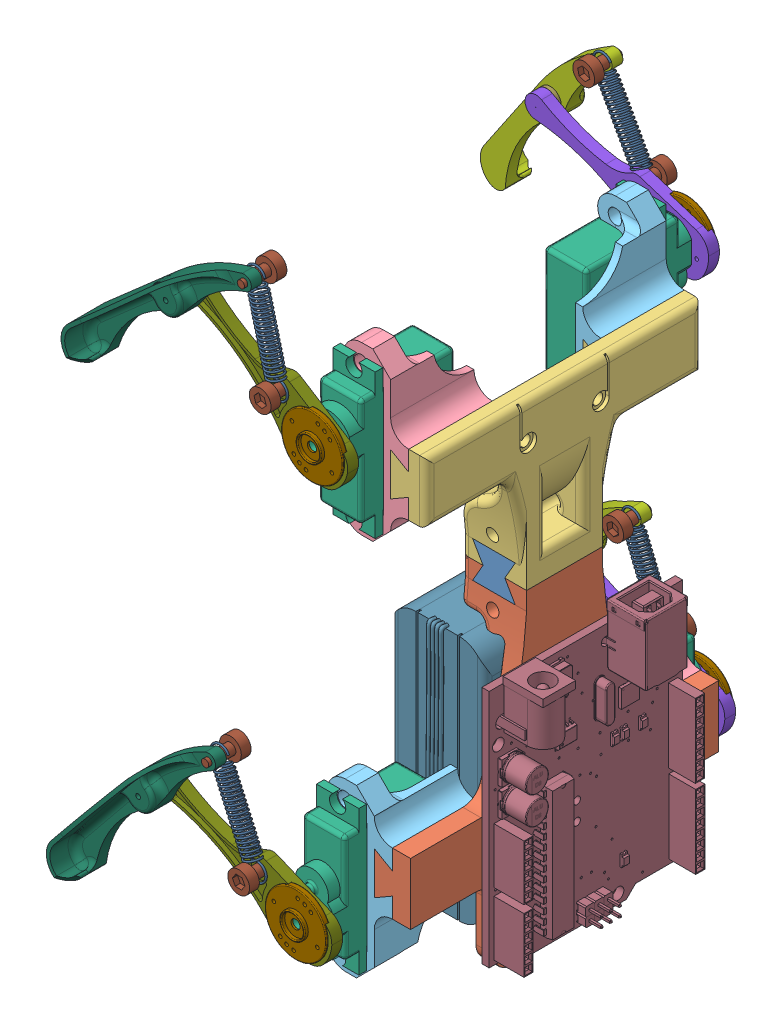
SolidWorks assembly puppy_v04_rigidSpine, configuration Default. Lengths in mm.
Overall size (92.78 186.66 133.4).
45 component instances, 16 part files, 43 mates.
Components (placement in the parent):
- rigid_spine-1: rigid_spine [Default] at (-4.6735 -0.0647 2.5101) size (11.77 10 21)
- body_front-1: body_front [Default] at (-4.6735 -65.0647 2.5101) x (0 0 1) z (1 0 0) size (85 87.52 18)
- body_rear-1: body_rear [Default] at (-4.6735 44.9353 2.5101) x (0 0 -1) z (1 0 0) size (76 45 18.96)
- HS-81MG_holder_empty-1: HS-81MG_holder_empty [Default] at (-13.6735 -61.0647 -34.9899) x (0 1 0) z (-1 0 0) size (46 23 17.9)
- HS-81MG_holder_empty-2: HS-81MG_holder_empty [Default] at (-13.6735 40.9353 35.5101) x (0 -1 0) z (-1 0 0) size (46 23 17.9)
- HS-81MG_holder_empty_mirror-1: HS-81MG_holder_empty_mirror [Default] at (-13.6735 -61.0647 40.0101) x (0 -1 0) z (-1 0 0) size (46 23 17.9)
- HS-81MG_holder_empty_mirror-2: HS-81MG_holder_empty_mirror [Default] at (-13.6735 40.9353 -30.4899) x (0 1 0) z (-1 0 0) size (46 23 17.9)
- HS-81MG-1: HS-81MG [Default] at (-13.6735 -61.0647 -33.0399) x (0 -1 0) z (1 0 0) size (39.8 33.1 11.7)
- HS-81MG-2: HS-81MG [Default] at (-13.6735 40.9353 -28.5399) x (0 1 0) z (-1 0 0) size (39.8 33.1 11.7)
- HS-81MG-3: HS-81MG [Default] at (-13.6735 -61.0647 38.0601) x (0 -1 0) z (-1 0 0) size (39.8 33.1 11.7)
- HS-81MG-4: HS-81MG [Default] at (-13.6735 40.9353 33.5601) x (0 1 0) z (1 0 0) size (39.8 33.1 11.7)
- AssemblyLeg_v2_left-1: AssemblyLeg_v2_left [Default] at (-36.9103 64.7215 -51.9489) x (0.561339 0.827586 0) z (-0.827586 0.561339 0) size (58.7 15.8 54.03)
  - LowerLeg_v2_left-1: LowerLeg_v2_left [Standard] at (-46.982 -8.259 12.3103) size (57 10 9.24)
  - UpperLeg_v2_left-1: UpperLeg_v2_left [Standard] at (-2.5862 -3.259 -29.832) x (-0.284896 0 0.958558) z (0 -1 0) size (52.5 13 3)
  - HS-81MG_horn-1: HS-81MG_horn [Default] at (-2.5862 -2.759 -29.832) x (-0.284896 0 0.958558) z (0 -1 0) size (17 17 5)
  - spring-2: spring [Default] at (-2.1428 -2.8777 -14.7648) x (0 1 0) z (0.451588 0 0.892227) size (5 5.5 30.5)
  - Schraube-2: Schraube [Standard] at (-3.2717 -0.159 -16.9953) x (0 -1 0) z (-0.448796 0 0.893634) size (9.7 6 6)
  - Schraube-3: Schraube [Standard] at (8.018 -5.359 5.3103) x (0 1 0) z (0.208882 0 0.977941) size (9.7 6 6)
  - spacerM3_1mm-1: spacerM3_1mm [Default] at (-13.982 -3.259 8.5103) x (1 0 0) z (0 1 0) size (6 6 1)
- AssemblyLeg_v2_left-2: AssemblyLeg_v2_left [Default] at (-34.5463 -44.4947 -56.4489) x (0.654125 0.756387 0) z (-0.756387 0.654125 0) size (58.7 15.8 54.03)
  - LowerLeg_v2_left-1: LowerLeg_v2_left [Standard] at (-46.982 -8.259 12.3103) size (57 10 9.24)
  - UpperLeg_v2_left-1: UpperLeg_v2_left [Standard] at (-2.5862 -3.259 -29.832) x (-0.284896 0 0.958558) z (0 -1 0) size (52.5 13 3)
  - HS-81MG_horn-1: HS-81MG_horn [Default] at (-2.5862 -2.759 -29.832) x (-0.284896 0 0.958558) z (0 -1 0) size (17 17 5)
  - spring-2: spring [Default] at (-2.1428 -2.8777 -14.7648) x (0 1 0) z (0.451588 0 0.892227) size (5 5.5 30.5)
  - Schraube-2: Schraube [Standard] at (-3.2717 -0.159 -16.9953) x (0 -1 0) z (-0.448796 0 0.893634) size (9.7 6 6)
  - Schraube-3: Schraube [Standard] at (8.018 -5.359 5.3103) x (0 1 0) z (0.208882 0 0.977941) size (9.7 6 6)
  - spacerM3_1mm-1: spacerM3_1mm [Default] at (-13.982 -3.259 8.5103) x (1 0 0) z (0 1 0) size (6 6 1)
- arduino-1: arduino [Default] at (4.3265 -17.0247 25.3301) x (0 -1 0) z (0 0 1) size (74.75 15.48 53.34)
- 1350 mAh 25C LiPo-1: 1350 mAh 25C LiPo [Default] at (-26.6735 -81.8 -14.4899) x (0 0 -1) z (0 -1 0) size (38.93 26 69.53)
- AssemblyLeg_v2_right-1: AssemblyLeg_v2_right [Default] at (-35.1872 -45.1369 56.9511) x (0.630908 0.775858 0) z (-0.775858 0.630908 0) size (59.24 15.8 54.03)
  - LowerLeg_v2_right-1: LowerLeg_v2_right [Standard] at (-46.982 -8.259 12.3103) size (57 10 9.24)
  - UpperLeg_v2_right-1: UpperLeg_v2_right [Standard] at (-2.5862 4.741 -29.832) x (-0.284896 0 0.958558) z (0 -1 0) size (52.5 13 3)
  - HS-81MG_horn-1: HS-81MG_horn [Default] at (-2.5862 -1.759 -29.832) x (-0.284896 0 0.958558) z (0 1 0) size (17 17 5)
  - spring-2: spring [Default] at (-2.1428 -2.0089 -14.7648) x (0 1 0) z (0.451588 0 0.892227) size (5 5.5 30.5)
  - Schraube-2: Schraube [Standard] at (-3.2717 -4.359 -16.9953) x (0 1 0) z (-0.11305 0 0.993589) size (9.7 6 6)
  - Schraube-3: Schraube [Standard] at (8.018 0.841 5.3103) x (0 -1 0) z (-0.709749 0 0.704455) size (9.7 6 6)
  - spacerM3_1mm-1: spacerM3_1mm [Default] at (-13.982 -2.259 8.5103) x (1 0 0) z (0 1 0) size (6 6 1)
- AssemblyLeg_v2_right-2: AssemblyLeg_v2_right [Default] at (-31.3986 69.9694 52.4511) x (0.751841 0.659344 0) z (-0.659344 0.751841 0) size (59.24 15.8 54.03)
  - LowerLeg_v2_right-1: LowerLeg_v2_right [Standard] at (-46.982 -8.259 12.3103) size (57 10 9.24)
  - UpperLeg_v2_right-1: UpperLeg_v2_right [Standard] at (-2.5862 4.741 -29.832) x (-0.284896 0 0.958558) z (0 -1 0) size (52.5 13 3)
  - HS-81MG_horn-1: HS-81MG_horn [Default] at (-2.5862 -1.759 -29.832) x (-0.284896 0 0.958558) z (0 1 0) size (17 17 5)
  - spring-2: spring [Default] at (-2.1428 -2.0089 -14.7648) x (0 1 0) z (0.451588 0 0.892227) size (5 5.5 30.5)
  - Schraube-2: Schraube [Standard] at (-3.2717 -4.359 -16.9953) x (0 1 0) z (-0.11305 0 0.993589) size (9.7 6 6)
  - Schraube-3: Schraube [Standard] at (8.018 0.841 5.3103) x (0 -1 0) z (-0.709749 0 0.704455) size (9.7 6 6)
  - spacerM3_1mm-1: spacerM3_1mm [Default] at (-13.982 -2.259 8.5103) x (1 0 0) z (0 1 0) size (6 6 1)
Mates (geometry in assembly coordinates):
- Coincident1: coincident anti-aligned: plane of rigid_spine-1 through (-4.6735 4.9353 13.0101) normal (0 1 0); plane of body_rear-1 through (4.3265 4.9353 2.9212) normal (0 -1 0)
- Coincident2: coincident anti-aligned: plane of rigid_spine-1 through (-7.6874 -10.4811 13.0101) normal (0.866025 -0.5 0); plane of body_rear-1 through (-1.6735 -0.0647 -7.9899) normal (-0.866025 0.5 0)
- Coincident3: coincident aligned: line of rigid_spine-1 through (-10.5602 4.9353 -7.9899) axis (0.5 -0.866025 0); line of body_rear-1 through (-10.5602 4.9353 -7.9899) axis (0.5 -0.866025 0)
- Coincident4: coincident anti-aligned: plane of rigid_spine-1 through (-4.6735 -5.0647 13.0101) normal (0 -1 0); plane of body_front-1 through (4.3265 -5.0647 2.5101) normal (0 1 0)
- Coincident5: coincident anti-aligned: plane of rigid_spine-1 through (-12.1874 -7.8831 13.0101) normal (-0.866025 0.5 0); plane of body_front-1 through (-7.6735 -0.0647 13.0101) normal (0.866025 -0.5 0)
- Coincident6: coincident aligned: line of rigid_spine-1 through (-10.5602 -5.0647 -7.9899) axis (0.5 0.866025 0); line of body_front-1 through (-10.5602 -5.0647 -7.9899) axis (0.5 0.866025 0)
- Coincident10: coincident anti-aligned: plane of body_rear-1 through (-5.6735 30.5485 17.5101) normal (-1 0 0); plane of HS-81MG_holder_empty-2 through (-5.6735 42.2347 -8.7889) normal (1 0 0)
- Coincident11: coincident anti-aligned: plane of body_rear-1 through (-0.6735 33.4353 17.5101) normal (0.5 -0.866025 0); plane of HS-81MG_holder_empty-2 through (8.0602 38.4776 5.8804) normal (-0.5 0.866025 0)
- Coincident12: coincident anti-aligned: line of body_rear-1 through (-5.6735 42.322 40.5101) axis (0.866025 -0.5 0); line of HS-81MG_holder_empty-2 through (-0.6735 39.4353 40.5101) axis (-0.866025 0.5 0)
- Coincident13: coincident anti-aligned: plane of body_front-1 through (-5.6735 -50.678 45.0101) normal (-1 0 0); plane of HS-81MG_holder_empty_mirror-1 through (-5.6735 -59.7653 -4.2889) normal (1 0 0)
- Coincident14: coincident anti-aligned: plane of body_front-1 through (-0.6735 -53.5647 45.0101) normal (0.5 0.866025 0); plane of HS-81MG_holder_empty_mirror-1 through (-10.559 -47.8573 10.3804) normal (-0.5 -0.866025 0)
- Coincident15: coincident anti-aligned: line of body_front-1 through (-5.6735 -62.4515 45.0101) axis (0.866025 0.5 0); line of HS-81MG_holder_empty_mirror-1 through (-0.6735 -59.5647 45.0101) axis (-0.866025 -0.5 0)
- Coincident16: coincident anti-aligned: plane of body_rear-1 through (-5.6735 30.5485 -12.4899) normal (-1 0 0); plane of HS-81MG_holder_empty_mirror-2 through (-5.6735 39.6359 13.8091) normal (1 0 0)
- Coincident17: coincident anti-aligned: plane of body_rear-1 through (-5.6735 42.322 -12.4899) normal (0.5 0.866025 0); plane of HS-81MG_holder_empty_mirror-2 through (8.0602 34.3929 -0.8602) normal (-0.5 -0.866025 0)
- Coincident18: coincident aligned: line of body_rear-1 through (-0.6735 33.4353 -35.4899) axis (-0.866025 -0.5 0); line of HS-81MG_holder_empty_mirror-2 through (-0.6735 33.4353 -35.4899) axis (-0.866025 -0.5 0)
- Coincident19: coincident anti-aligned: plane of body_front-1 through (-5.6735 -50.678 45.0101) normal (-1 0 0); plane of HS-81MG_holder_empty-1 through (-5.6735 -62.3641 9.3091) normal (1 0 0)
- Coincident20: coincident anti-aligned: plane of body_front-1 through (-0.6735 -53.5647 45.0101) normal (0.5 0.866025 0); plane of HS-81MG_holder_empty-1 through (8.0602 -58.6071 -5.3602) normal (-0.5 -0.866025 0)
- Coincident23: coincident anti-aligned: line of body_front-1 through (-5.6735 -62.4515 -39.9899) axis (0.866025 0.5 0); line of HS-81MG_holder_empty-1 through (-0.6735 -59.5647 -39.9899) axis (-0.866025 -0.5 0)
- Coincident24: coincident anti-aligned: plane of HS-81MG_holder_empty-1 through (-21.6735 -62.3641 -39.9899) normal (0 0 -1); plane of HS-81MG-1 through (-7.8235 -80.9647 -39.9899) normal (0 0 1)
- Concentric1: concentric aligned: cylinder of HS-81MG_holder_empty-1 through (-13.6735 -79.1647 -19.9899) axis (0 0 -1) radius 2; cylinder of HS-81MG-1 through (-13.6735 -79.1647 -33.6259) axis (0 0 -1) radius 2.25
- Concentric2: concentric aligned: cylinder of HS-81MG_holder_empty-1 through (-13.6735 -42.9647 -19.9899) axis (0 0 -1) radius 2; cylinder of HS-81MG-1 through (-13.6735 -42.9647 -33.6259) axis (0 0 -1) radius 2.25
- Coincident25: coincident anti-aligned: plane of HS-81MG_holder_empty_mirror-2 through (-21.6735 39.6359 -35.4899) normal (0 0 -1); plane of HS-81MG-2 through (-19.5235 60.8353 -35.4899) normal (0 0 1)
- Concentric3: concentric aligned: cylinder of HS-81MG_holder_empty_mirror-2 through (-13.6735 22.8353 -15.4899) axis (0 0 -1) radius 2; cylinder of HS-81MG-2 through (-13.6735 22.8353 -29.1259) axis (0 0 -1) radius 2.25
- Concentric4: concentric aligned: cylinder of HS-81MG_holder_empty_mirror-2 through (-13.6735 59.0353 -15.4899) axis (0 0 -1) radius 2; cylinder of HS-81MG-2 through (-13.6735 59.0353 -29.1259) axis (0 0 -1) radius 2.25
- Coincident26: coincident anti-aligned: plane of HS-81MG_holder_empty_mirror-1 through (-21.6735 -59.7653 45.0101) normal (0 0 1); plane of HS-81MG-3 through (-19.5235 -41.1647 45.0101) normal (0 0 -1)
- Concentric5: concentric aligned: cylinder of HS-81MG_holder_empty_mirror-1 through (-13.6735 -42.9647 25.0101) axis (0 0 1) radius 2; cylinder of HS-81MG-3 through (-13.6735 -42.9647 38.6461) axis (0 0 1) radius 2.25
- Concentric6: concentric aligned: cylinder of HS-81MG_holder_empty_mirror-1 through (-13.6735 -79.1647 25.0101) axis (0 0 1) radius 2; cylinder of HS-81MG-3 through (-13.6735 -79.1647 38.6461) axis (0 0 1) radius 2.25
- Coincident27: coincident anti-aligned: plane of HS-81MG_holder_empty-2 through (-21.6735 42.2347 40.5101) normal (0 0 1); plane of HS-81MG-4 through (-7.8235 60.8353 40.5101) normal (0 0 -1)
- Concentric7: concentric aligned: cylinder of HS-81MG_holder_empty-2 through (-13.6735 22.8353 20.5101) axis (0 0 1) radius 2; cylinder of HS-81MG-4 through (-13.6735 22.8353 34.1461) axis (0 0 1) radius 2.25
- Concentric8: concentric aligned: cylinder of HS-81MG_holder_empty-2 through (-13.6735 59.0353 20.5101) axis (0 0 1) radius 2; cylinder of HS-81MG-4 through (-13.6735 59.0353 34.1461) axis (0 0 1) radius 2.25
- Coincident30: coincident anti-aligned: plane of body_front-1 through (4.3265 -65.0647 2.5101) normal (1 0 0); plane of arduino-1 through (4.3265 16.5596 -1.3582) normal (-1 0 0)
- Coincident31: coincident anti-aligned: plane of body_front-1 through (-0.6735 -65.0647 2.5101) normal (-1 0 0); plane of 1350 mAh 25C LiPo-1 through (-0.6735 -13.8 -14.4899) normal (1 0 0)
- Width1: width aligned: plane of HS-81MG_holder_empty-1 through (-21.6735 -62.3641 -16.9899) normal (0 0 1); plane of HS-81MG_holder_empty_mirror-1 through (-21.6735 -59.7653 22.0101) normal (0 0 -1); plane of 1350 mAh 25C LiPo-1 through (-26.6735 -13.8 19.5101) normal (0 0 1); plane of 1350 mAh 25C LiPo-1 through (-26.6735 -13.8 -14.4899) normal (0 0 -1)
- Concentric11: concentric anti-aligned: cylinder of body_front-1 through (-0.6735 -83.0647 17.7101) axis (1 0 0) radius 1.5; cylinder of arduino-1 through (6.3265 -83.0647 17.7101) axis (-1 0 0) radius 1.6
- Concentric12: concentric anti-aligned: cylinder of body_front-1 through (-0.6735 -83.0647 -10.2299) axis (1 0 0) radius 1.5; cylinder of arduino-1 through (6.3265 -83.0647 -10.2299) axis (-1 0 0) radius 1.6
- Concentric13: concentric anti-aligned: cylinder of AssemblyLeg_v2_left-2/HS-81MG_horn-1 through (-13.6735 -65.9647 -52.1899) axis (0 0 -1) radius 2.5; cylinder of HS-81MG-1 through (-13.6735 -65.9647 -53.1899) axis (0 0 1) radius 1.5
- Coincident34: coincident anti-aligned: plane of HS-81MG-1 through (-13.6735 -65.9647 -53.1899) normal (0 0 -1); plane of AssemblyLeg_v2_left-2/HS-81MG_horn-1 through (-13.6735 -65.9647 -53.1899) normal (0 0 1)
- Concentric14: concentric anti-aligned: cylinder of HS-81MG-2 through (-13.6735 45.8353 -48.6899) axis (0 0 1) radius 1.5; cylinder of AssemblyLeg_v2_left-1/HS-81MG_horn-1 through (-13.6735 45.8353 -47.6899) axis (0 0 -1) radius 2.5
- Coincident35: coincident anti-aligned: plane of HS-81MG-2 through (-13.6735 45.8353 -48.6899) normal (0 0 -1); plane of AssemblyLeg_v2_left-1/HS-81MG_horn-1 through (-13.6735 45.8353 -48.6899) normal (0 0 1)
- Concentric15: concentric anti-aligned: cylinder of HS-81MG-3 through (-13.6735 -65.9647 58.2101) axis (0 0 -1) radius 1.5; cylinder of AssemblyLeg_v2_right-1/HS-81MG_horn-1 through (-13.6735 -65.9647 57.2101) axis (0 0 1) radius 2.5
- Coincident36: coincident anti-aligned: plane of HS-81MG-3 through (-13.6735 -65.9647 58.2101) normal (0 0 1); plane of AssemblyLeg_v2_right-1/HS-81MG_horn-1 through (-13.6735 -65.9647 58.2101) normal (0 0 -1)
- Concentric16: concentric anti-aligned: cylinder of HS-81MG-4 through (-13.6735 45.8353 53.7101) axis (0 0 -1) radius 1.5; cylinder of AssemblyLeg_v2_right-2/HS-81MG_horn-1 through (-13.6735 45.8353 52.7101) axis (0 0 1) radius 2.5
- Coincident37: coincident anti-aligned: plane of HS-81MG-4 through (-13.6735 45.8353 53.7101) normal (0 0 1); plane of AssemblyLeg_v2_right-2/HS-81MG_horn-1 through (-13.6735 45.8353 53.7101) normal (0 0 -1)
